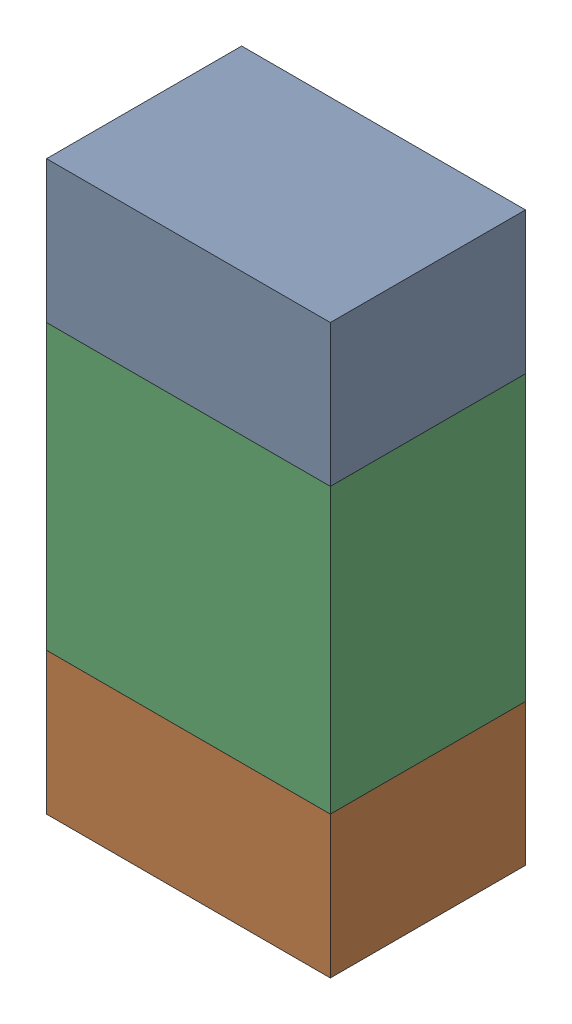
SolidWorks assembly R20, configuration ﾃﾞﾌｫﾙﾄ. Lengths in mm.
Overall size (0.8 1.6 0.55).
6 component instances, 2 part files, 0 mates.
Components (placement in the parent):
- 689261784-1: 689261784 [ﾃﾞﾌｫﾙﾄ] at (73.5001 53.8499 0) size (0.8 0.4 0.55)
  - Extruded_34-1: Extruded_34 [ﾃﾞﾌｫﾙﾄ] at origin size (0.8 0.4 0.55)
- 689261784-2: 689261784 [ﾃﾞﾌｫﾙﾄ] at (73.5001 52.6499 0) size (0.8 0.4 0.55)
  - Extruded_34-1: Extruded_34 [ﾃﾞﾌｫﾙﾄ] at origin size (0.8 0.4 0.55)
- 689261648-1: 689261648 [ﾃﾞﾌｫﾙﾄ] at (73.5001 53.25 0) size (0.8 0.8 0.55)
  - Extruded_33-1: Extruded_33 [ﾃﾞﾌｫﾙﾄ] at origin size (0.8 0.8 0.55)
